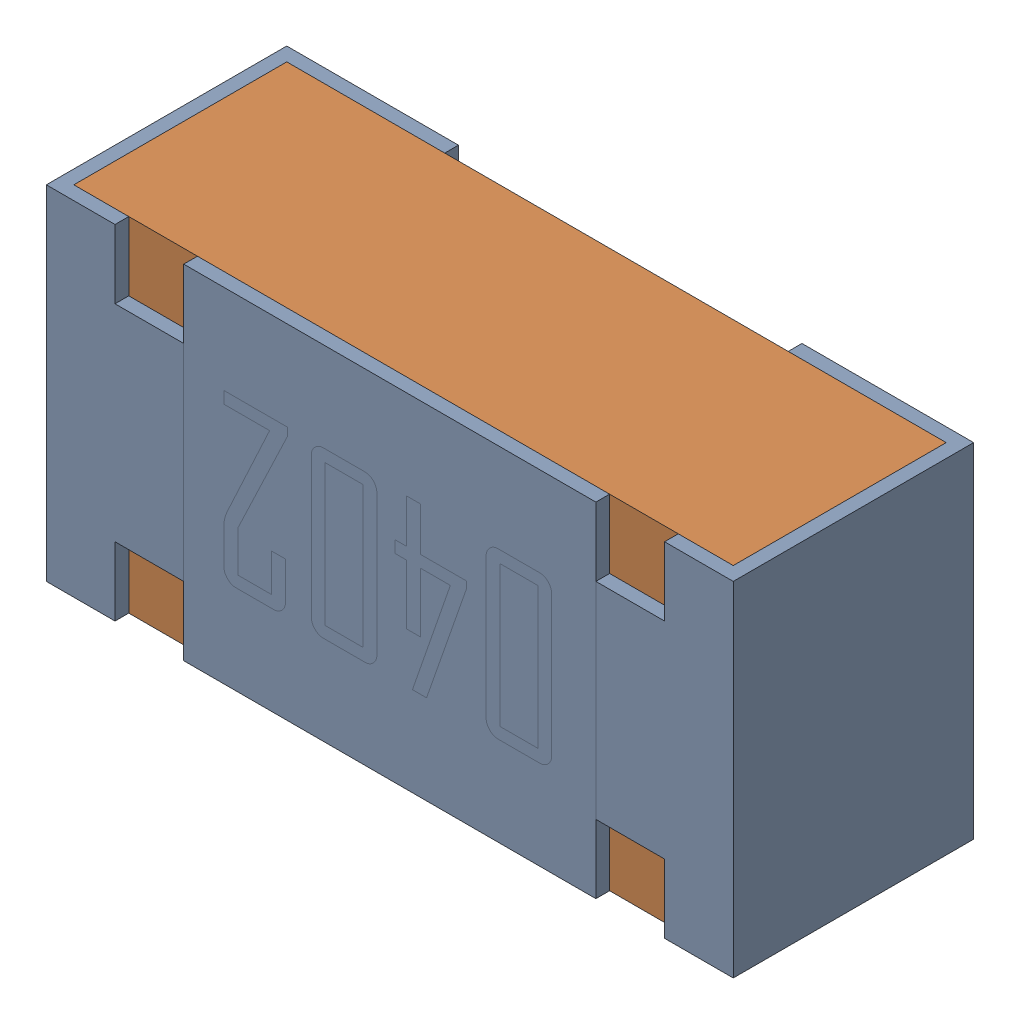
SolidWorks assembly R2, configuration Default. Lengths in mm.
Overall size (1 0.5 0.35).
3 component instances, 2 part files, 0 mates.
Components (placement in the parent):
- R2-subassembly-1-1: R2-subassembly-1 [Default] at (-15.4999 2.625 0) x (-1 0 0) z (0 1 0) size (1 0.35 0.5)
  - 0402 resistor-1: 0402 resistor [Default] at origin size (1 0.35 0.5)
  - 0402 resistor-1-1: 0402 resistor-1 [Default] at origin size (0.96 0.31 0.5)
